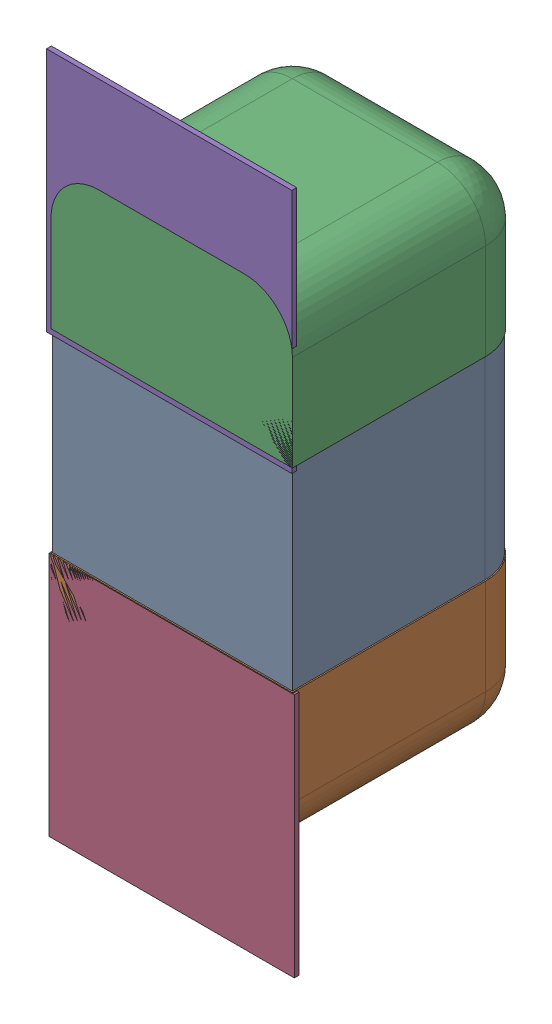
SolidWorks assembly C113, configuration Défaut. Lengths in mm.
Overall size (0.51 1.41 0.5).
8 component instances, 4 part files, 0 mates.
Components (placement in the parent):
- 6501210464-1: 6501210464 [Défaut] at (18.7731 -21.648 -2.0818) x (0 1 0) z (-1 0 0) size (1 0.5 0.5)
  - Open CASCADE STEP translator 7.5 2.33.1.1-1: Open CASCADE STEP translator 7.5 2.33.1.1 [Défaut] at origin size (0.4 0.5 0.5)
  - Open CASCADE STEP translator 7.5 2.33.1.2-1: Open CASCADE STEP translator 7.5 2.33.1.2 [Défaut] at origin size (0.3 0.5 0.5)
  - Open CASCADE STEP translator 7.5 2.33.1.3-1: Open CASCADE STEP translator 7.5 2.33.1.3 [Défaut] at origin size (0.3 0.5 0.5)
- 6504207776-1: 6504207776 [Défaut] at (18.773 -22.1053 -2.0918) size (0.51 0.51 0.01)
  - Extruded-1: Extruded [Défaut] at origin size (0.51 0.51 0.01)
- 6504207776-2: 6504207776 [Défaut] at (18.7679 -21.203 -2.0918) size (0.51 0.51 0.01)
  - Extruded-1: Extruded [Défaut] at origin size (0.51 0.51 0.01)
